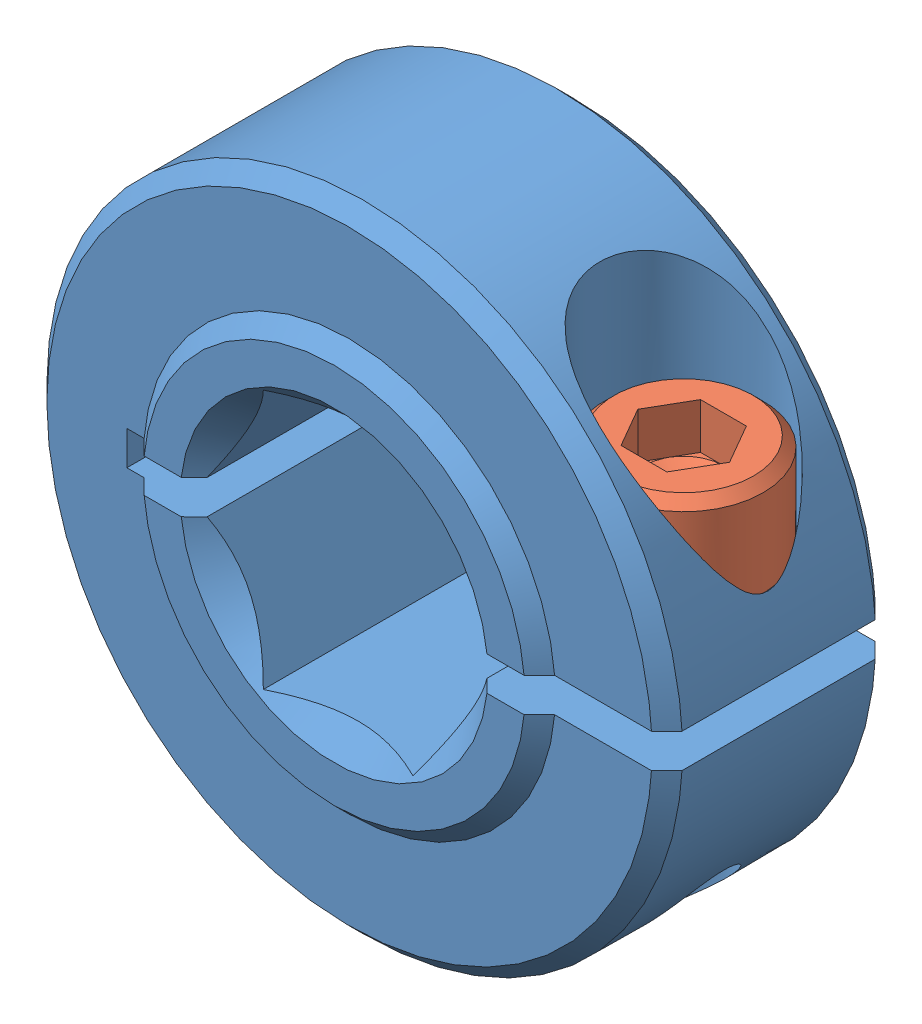
SolidWorks assembly GE-22438, configuration Default. Lengths in mm.
Overall size (31.73 31.75 13.78).
2 component instances, 2 part files, 0 mates.
Components (placement in the parent):
- am-1238a 500Hex Collar Clamp Body-1: am-1238a 500Hex Collar Clamp Body [Default] at (-94.2794 15.3021 33.01) size (31.73 31.75 13.78)
- 10-32x0500_shcs_HX-SHCS 0.19-32x1.375x1-C-1: 10-32x0500_shcs_HX-SHCS 0.19-32x1.375x1-C [Default] at (-83.1669 24.154 39.36) x (0 -1 0) z (0 0 1) size (17.53 7.94 7.94)
